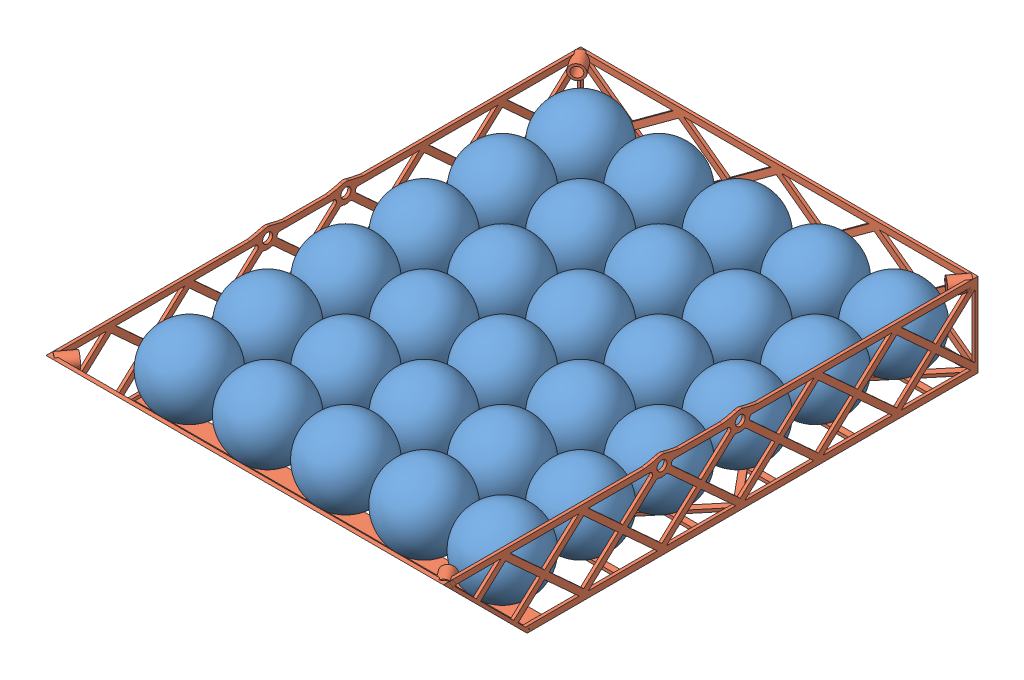
SolidWorks assembly GliderColonistsLayout, configuration Default. Lengths in mm.
Overall size (225.09 52.72 283.26).
31 component instances, 2 part files, 5 mates.
Components (placement in the parent):
- PingPongBall-1: PingPongBall [Default] at (91.1225 193.2296 86.65) x (0.318433 -0.943803 -0.088524) z (0.332607 0.023792 0.942765) size (40.64 40.64 40.64)
- PingPongBall-146: PingPongBall [Default] at (91.1225 193.2296 46.01) x (0.318433 -0.943803 -0.088524) z (0.332607 0.023792 0.942765) size (40.64 40.64 40.64)
- PingPongBall-147: PingPongBall [Default] at (91.1225 193.2296 5.37) x (0.318433 -0.943803 -0.088524) z (0.332607 0.023792 0.942765) size (40.64 40.64 40.64)
- PingPongBall-148: PingPongBall [Default] at (91.1225 193.2296 -35.27) x (0.318433 -0.943803 -0.088524) z (0.332607 0.023792 0.942765) size (40.64 40.64 40.64)
- PingPongBall-149: PingPongBall [Default] at (91.1225 193.2296 -75.91) x (0.318433 -0.943803 -0.088524) z (0.332607 0.023792 0.942765) size (40.64 40.64 40.64)
- PingPongBall-150: PingPongBall [Default] at (91.1225 193.2296 -116.55) x (0.318433 -0.943803 -0.088524) z (0.332607 0.023792 0.942765) size (40.64 40.64 40.64)
- PingPongBall-151: PingPongBall [Default] at (50.4825 193.2296 86.65) x (0.318433 -0.943803 -0.088524) z (0.332607 0.023792 0.942765) size (40.64 40.64 40.64)
- PingPongBall-152: PingPongBall [Default] at (50.4825 193.2296 46.01) x (0.318433 -0.943803 -0.088524) z (0.332607 0.023792 0.942765) size (40.64 40.64 40.64)
- PingPongBall-153: PingPongBall [Default] at (50.4825 193.2296 5.37) x (0.318433 -0.943803 -0.088524) z (0.332607 0.023792 0.942765) size (40.64 40.64 40.64)
- PingPongBall-154: PingPongBall [Default] at (50.4825 193.2296 -35.27) x (0.318433 -0.943803 -0.088524) z (0.332607 0.023792 0.942765) size (40.64 40.64 40.64)
- PingPongBall-155: PingPongBall [Default] at (50.4825 193.2296 -75.91) x (0.318433 -0.943803 -0.088524) z (0.332607 0.023792 0.942765) size (40.64 40.64 40.64)
- PingPongBall-156: PingPongBall [Default] at (50.4825 193.2296 -116.55) x (0.318433 -0.943803 -0.088524) z (0.332607 0.023792 0.942765) size (40.64 40.64 40.64)
- PingPongBall-157: PingPongBall [Default] at (9.8425 193.2296 86.65) x (0.318433 -0.943803 -0.088524) z (0.332607 0.023792 0.942765) size (40.64 40.64 40.64)
- PingPongBall-158: PingPongBall [Default] at (9.8425 193.2296 46.01) x (0.318433 -0.943803 -0.088524) z (0.332607 0.023792 0.942765) size (40.64 40.64 40.64)
- PingPongBall-159: PingPongBall [Default] at (9.8425 193.2296 5.37) x (0.318433 -0.943803 -0.088524) z (0.332607 0.023792 0.942765) size (40.64 40.64 40.64)
- PingPongBall-160: PingPongBall [Default] at (9.8425 193.2296 -35.27) x (0.318433 -0.943803 -0.088524) z (0.332607 0.023792 0.942765) size (40.64 40.64 40.64)
- PingPongBall-161: PingPongBall [Default] at (9.8425 193.2296 -75.91) x (0.318433 -0.943803 -0.088524) z (0.332607 0.023792 0.942765) size (40.64 40.64 40.64)
- PingPongBall-162: PingPongBall [Default] at (9.8425 193.2296 -116.55) x (0.318433 -0.943803 -0.088524) z (0.332607 0.023792 0.942765) size (40.64 40.64 40.64)
- DroneFrame_Ver_2-1: DroneFrame_Ver_2 [Default] at (9.8425 171.3221 -14.95) size (206.38 45.4 277.68)
- PingPongBall-187: PingPongBall [Default] at (-30.7975 193.2296 86.65) x (0.318433 -0.943803 -0.088524) z (0.332607 0.023792 0.942765) size (40.64 40.64 40.64)
- PingPongBall-188: PingPongBall [Default] at (-30.7975 193.2296 46.01) x (0.318433 -0.943803 -0.088524) z (0.332607 0.023792 0.942765) size (40.64 40.64 40.64)
- PingPongBall-189: PingPongBall [Default] at (-30.7975 193.2296 5.37) x (0.318433 -0.943803 -0.088524) z (0.332607 0.023792 0.942765) size (40.64 40.64 40.64)
- PingPongBall-190: PingPongBall [Default] at (-30.7975 193.2296 -35.27) x (0.318433 -0.943803 -0.088524) z (0.332607 0.023792 0.942765) size (40.64 40.64 40.64)
- PingPongBall-191: PingPongBall [Default] at (-30.7975 193.2296 -75.91) x (0.318433 -0.943803 -0.088524) z (0.332607 0.023792 0.942765) size (40.64 40.64 40.64)
- PingPongBall-192: PingPongBall [Default] at (-30.7975 193.2296 -116.55) x (0.318433 -0.943803 -0.088524) z (0.332607 0.023792 0.942765) size (40.64 40.64 40.64)
- PingPongBall-193: PingPongBall [Default] at (-71.4375 193.2296 86.65) x (0.318433 -0.943803 -0.088524) z (0.332607 0.023792 0.942765) size (40.64 40.64 40.64)
- PingPongBall-194: PingPongBall [Default] at (-71.4375 193.2296 46.01) x (0.318433 -0.943803 -0.088524) z (0.332607 0.023792 0.942765) size (40.64 40.64 40.64)
- PingPongBall-195: PingPongBall [Default] at (-71.4375 193.2296 5.37) x (0.318433 -0.943803 -0.088524) z (0.332607 0.023792 0.942765) size (40.64 40.64 40.64)
- PingPongBall-196: PingPongBall [Default] at (-71.4375 193.2296 -35.27) x (0.318433 -0.943803 -0.088524) z (0.332607 0.023792 0.942765) size (40.64 40.64 40.64)
- PingPongBall-197: PingPongBall [Default] at (-71.4375 193.2296 -75.91) x (0.318433 -0.943803 -0.088524) z (0.332607 0.023792 0.942765) size (40.64 40.64 40.64)
- PingPongBall-198: PingPongBall [Default] at (-71.4375 193.2296 -116.55) x (0.318433 -0.943803 -0.088524) z (0.332607 0.023792 0.942765) size (40.64 40.64 40.64)
Mates (geometry in assembly coordinates):
- Tangent6: tangent anti-aligned: sphere of PingPongBall-150; plane of DroneFrame_Ver_2-1 through (9.8425 172.9096 -136.87) normal (0 0 1)
- Tangent7: tangent anti-aligned: sphere of PingPongBall-150; plane of DroneFrame_Ver_2-1 through (111.4425 172.9096 -14.95) normal (-1 0 0)
- Tangent8: tangent anti-aligned: sphere of PingPongBall-150; plane of DroneFrame_Ver_2-1 through (9.8425 172.9096 -14.95) normal (0 1 0)
- Parallel1: parallel anti-aligned: plane of DroneFrame_Ver_2-1 through (9.8425 172.9096 -138.4575) normal (0 0 -1)
- Parallel2: parallel anti-aligned: plane of DroneFrame_Ver_2-1 through (-93.345 172.9096 -14.95) normal (-1 0 0)
